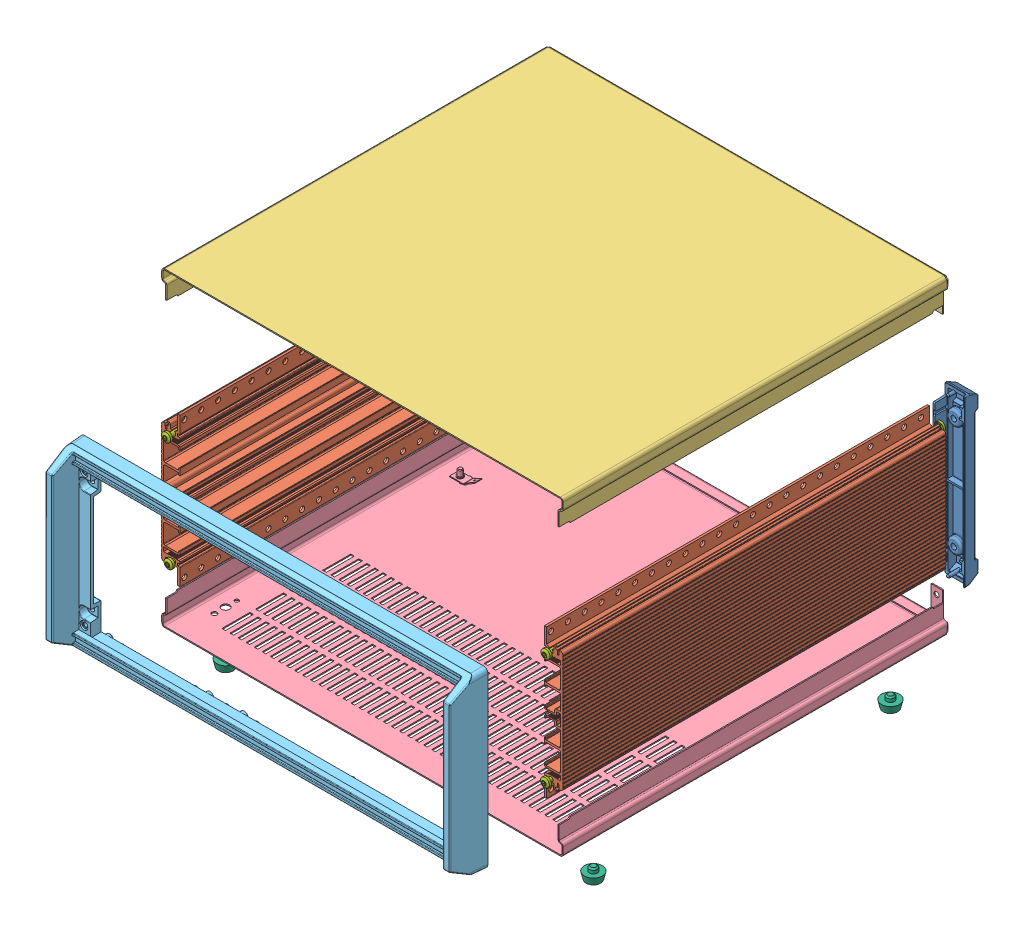
SolidWorks assembly 14576-145, configuration По умолчанию. Lengths in mm.
Overall size (363.7 323.07 471.63).
19 component instances, 7 part files, 27 mates.
Components (placement in the parent):
- RUECKFUSS-1: RUECKFUSS [По умолчанию] at (-181.1098 56.8309 -365.5866) x (-0.000005 0 1) z (-1 0 -0.000005) size (20.51 147.89 20.81)
- RUECKFUSS-2: RUECKFUSS [По умолчанию] at (181.1098 56.7192 -382.7925) x (0.000005 0 1) z (1 0 -0.000005) size (20.51 147.89 20.81)
- SEITENWAND-3HE-386T-1: SEITENWAND-3HE-386T [По умолчанию] at (164.6599 61.7249 -183.4869) x (0 1 0) z (0 0 -1) size (132.55 16.5 341.6)
- SEITENWAND-3HE-386T-2: SEITENWAND-3HE-386T [По умолчанию] at (-164.6599 51.8251 -183.4869) x (0 -1 0) z (0 0 -1) size (132.55 16.5 341.6)
- MANTEL-OB-----386T------63TE-1: MANTEL-OB-----386T------63TE [По умолчанию] at (-105.2767 229.3578 -281.6964) x (-1 0 0) z (0 -1 0) size (358.09 344.85 32)
- MANTEL-UN-----386T------63TE-1: MANTEL-UN-----386T------63TE [По умолчанию] at (105.7168 -47.8176 -281.6964) x (1 0 0) z (0 1 0) size (358.09 344.85 32)
- RAHMEN-3HE-63TE-1: RAHMEN-3HE-63TE [По умолчанию] at (0.0099 56.7749 69.2144) size (363.7 155.5 35.01)
- 60224009-1: 60224009 [По умолчанию] at (-108.0487 -15.5421 -42.4869) x (1 0 0) z (0 0 1) size (16 11.2 16)
- 60224009-2: 60224009 [По умолчанию] at (-108.0487 -15.5421 -307.4869) x (1 0 0) z (0 0 1) size (16 11.2 16)
- 60224009-3: 60224009 [По умолчанию] at (220.0313 -15.5422 -42.4869) x (1 0 0) z (0 0 1) size (16 11.2 16)
- 60224009-4: 60224009 [По умолчанию] at (220.0313 -15.5422 -307.4869) x (1 0 0) z (0 0 1) size (16 11.2 16)
- FLKOSHR-T-M-4-X16--1: FLKOSHR-T-M-4-X16- [По умолчанию] at (-168.3599 106.2501 2.3059) size (8.2 9.29 19.12)
- FLKOSHR-T-M-4-X16--2: FLKOSHR-T-M-4-X16- [По умолчанию] at (-168.3599 7.3001 0.1199) size (8.2 9.29 19.12)
- FLKOSHR-T-M-4-X16--3: FLKOSHR-T-M-4-X16- [По умолчанию] at (168.3599 106.2499 0.5037) size (8.2 9.29 19.12)
- FLKOSHR-T-M-4-X16--4: FLKOSHR-T-M-4-X16- [По умолчанию] at (168.3599 7.2999 1.0609) size (8.2 9.29 19.12)
- FLKOSHR-T-M-4-X16--5: FLKOSHR-T-M-4-X16- [По умолчанию] at (168.3599 7.2999 -344.7548) x (-1 0 0) z (0 0 -1) size (8.2 9.29 19.12)
- FLKOSHR-T-M-4-X16--6: FLKOSHR-T-M-4-X16- [По умолчанию] at (168.3599 106.2499 -344.7915) x (-1 0 0) z (0 0 -1) size (8.2 9.29 19.12)
- FLKOSHR-T-M-4-X16--7: FLKOSHR-T-M-4-X16- [По умолчанию] at (-168.3599 7.3001 -343.6567) x (-1 0 0) z (0 0 -1) size (8.2 9.29 19.12)
- FLKOSHR-T-M-4-X16--8: FLKOSHR-T-M-4-X16- [По умолчанию] at (-168.3599 106.2501 -343.7886) x (-1 0 0) z (0 0 -1) size (8.2 9.29 19.12)
Mates (geometry in assembly coordinates):
- Концентричный1: concentric anti-aligned: cylinder of MANTEL-UN-----386T------63TE-1 through (-163.8199 -47.8176 -307.4869) axis (0 1 0) radius 3.5; circle of 60224009-2
- Концентричный2: concentric anti-aligned: cylinder of MANTEL-UN-----386T------63TE-1 through (-163.8199 -47.8176 -42.4869) axis (0 1 0) radius 3.5; circle of 60224009-1
- Концентричный3: concentric anti-aligned: cylinder of MANTEL-UN-----386T------63TE-1 through (164.2601 -47.8176 -42.4869) axis (0 1 0) radius 3.5; circle of 60224009-3
- Концентричный4: concentric anti-aligned: cylinder of MANTEL-UN-----386T------63TE-1 through (164.2601 -47.8176 -307.4869) axis (0 1 0) radius 3.5; circle of 60224009-4
- Совпадение1: coincident aligned: plane of 60224009-2 through (-166.3499 -82.5094 -310.0169) normal (0 1 0); plane of 60224009-4 through (161.7301 -82.5095 -310.0169) normal (0 1 0)
- Совпадение2: coincident aligned: plane of 60224009-1 through (-166.3499 -82.5094 -45.0169) normal (0 1 0); plane of 60224009-2 through (-166.3499 -82.5094 -310.0169) normal (0 1 0)
- Совпадение3: coincident aligned: plane of 60224009-1 through (-166.3499 -82.5094 -45.0169) normal (0 1 0); plane of 60224009-3 through (161.7301 -82.5095 -45.0169) normal (0 1 0)
- Совпадение4: coincident anti-aligned: plane of SEITENWAND-3HE-386T-1 through (175.7601 5.4591 -0.4869) normal (-1 0 0); plane of MANTEL-UN-----386T------63TE-1 through (175.7601 -36.1476 -343.6169) normal (1 0 0)
- Расстояние1: distance = 0 mm: plane of SEITENWAND-3HE-386T-1 through (179.5726 -11.2569 -0.4869) normal (0 0 1); point of MANTEL-UN-----386T------63TE-1
- Перпендикулярность1: perpendicular: plane of SEITENWAND-3HE-386T-1 through (175.3599 15.8249 -0.4869) normal (0 1 0); plane of MANTEL-UN-----386T------63TE-1 through (-196.7239 -23.1426 -0.4869) normal (0 0 1)
- Совпадение6: coincident anti-aligned: plane of SEITENWAND-3HE-386T-1 through (175.7601 108.0907 -0.4869) normal (-1 0 0); plane of MANTEL-OB-----386T------63TE-1 through (175.7601 217.6878 -0.4569) normal (1 0 0)
- Расстояние2: distance = 0 mm: plane of SEITENWAND-3HE-386T-1 through (179.5726 -11.2569 -0.4869) normal (0 0 1); point of MANTEL-OB-----386T------63TE-1
- Перпендикулярность2: perpendicular: plane of SEITENWAND-3HE-386T-1 through (164.0599 79.9999 -0.4869) normal (0 1 0); plane of MANTEL-OB-----386T------63TE-1 through (197.1641 204.6828 -0.4869) normal (0 0 1)
- Концентричный5: concentric anti-aligned: circle of SEITENWAND-3HE-386T-1; circle of FLKOSHR-T-M-4-X16--6
- Концентричный6: concentric aligned: circle of SEITENWAND-3HE-386T-1; circle of FLKOSHR-T-M-4-X16--5
- Концентричный7: concentric anti-aligned: circle of SEITENWAND-3HE-386T-2; circle of FLKOSHR-T-M-4-X16--7
- Концентричный8: concentric aligned: circle of SEITENWAND-3HE-386T-2; circle of FLKOSHR-T-M-4-X16--8
- Совпадение8: coincident: cone of RUECKFUSS-2 through (168.3599 106.2499 -366.9044) axis (0 0 1); circle of FLKOSHR-T-M-4-X16--6
- Перпендикулярность3: perpendicular: plane of RUECKFUSS-2 through (181.1099 123.775 -368.9042) normal (0 -0.999391 -0.034899); plane of SEITENWAND-3HE-386T-1 through (177.0599 80.8391 -0.4869) normal (-1 0 0)
- Концентричный9: concentric aligned: cylinder of RUECKFUSS-1 through (-168.3599 106.2501 -349.6985) axis (0 0 1) radius 34.9055; circle of FLKOSHR-T-M-4-X16--8
- Перпендикулярность4: perpendicular: plane of RUECKFUSS-1 through (-181.1099 123.7751 -351.6984) normal (0 -0.999391 -0.034899); plane of SEITENWAND-3HE-386T-2 through (-177.0599 80.8392 -0.4869) normal (1 0 0)
- Концентричный10: concentric aligned: circle of SEITENWAND-3HE-386T-2; circle of FLKOSHR-T-M-4-X16--1
- Концентричный11: concentric anti-aligned: circle of SEITENWAND-3HE-386T-2; circle of FLKOSHR-T-M-4-X16--2
- Концентричный12: concentric anti-aligned: circle of SEITENWAND-3HE-386T-1; circle of FLKOSHR-T-M-4-X16--3
- Концентричный13: concentric aligned: circle of SEITENWAND-3HE-386T-1; circle of FLKOSHR-T-M-4-X16--4
- Концентричный14: concentric anti-aligned: cylinder of RAHMEN-3HE-63TE-1 through (168.3599 7.2999 72.2144) axis (0 0 1) radius 26.1799; circle of FLKOSHR-T-M-4-X16--4
- Перпендикулярность5: perpendicular: plane of SEITENWAND-3HE-386T-1 through (162.5599 108.4499 -0.4869) normal (-1 0 0); plane of RAHMEN-3HE-63TE-1 through (181.9174 129.2249 85.3144) normal (0 -1 0)
